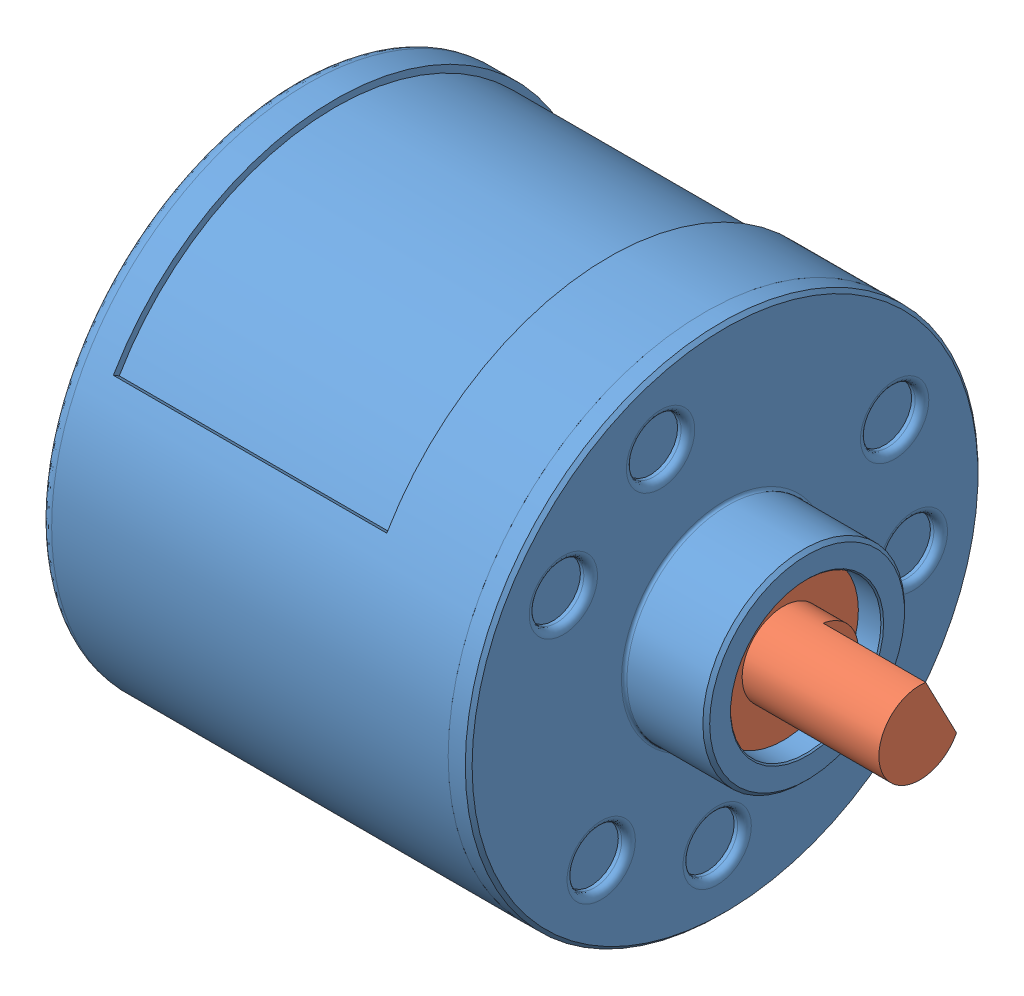
SolidWorks assembly Encoder, configuration Default. Lengths in mm.
Overall size (91.5 75 75).
2 component instances, 2 part files, 2 mates.
Components (placement in the parent):
- Inverted_Pendulum_Encoder_1-1: Inverted_Pendulum_Encoder_1 [Varsayılan] at (-16.9806 49.6671 74.1496) size (75 75 75)
- Inverted_Pendulum_Encoder_2-1: Inverted_Pendulum_Encoder_2 [Default] at (51.5194 49.6671 74.1496) x (0 -0.461857 0.886954) z (1 0 0) size (22 22 23)
Mates (geometry in assembly coordinates):
- Concentric1: concentric aligned: cylinder of Inverted_Pendulum_Encoder_1-1 through (58.0194 49.6671 74.1496) axis (-1 0 0) radius 11; cylinder of Inverted_Pendulum_Encoder_2-1 through (54.5194 49.6671 74.1496) axis (-1 0 0) radius 11
- Distance1: distance = 3.5 mm aligned: plane of Inverted_Pendulum_Encoder_2-1 through (54.5194 49.6671 74.1496) normal (1 0 0); plane of Inverted_Pendulum_Encoder_1-1 through (58.0194 49.6671 74.1496) normal (1 0 0)
